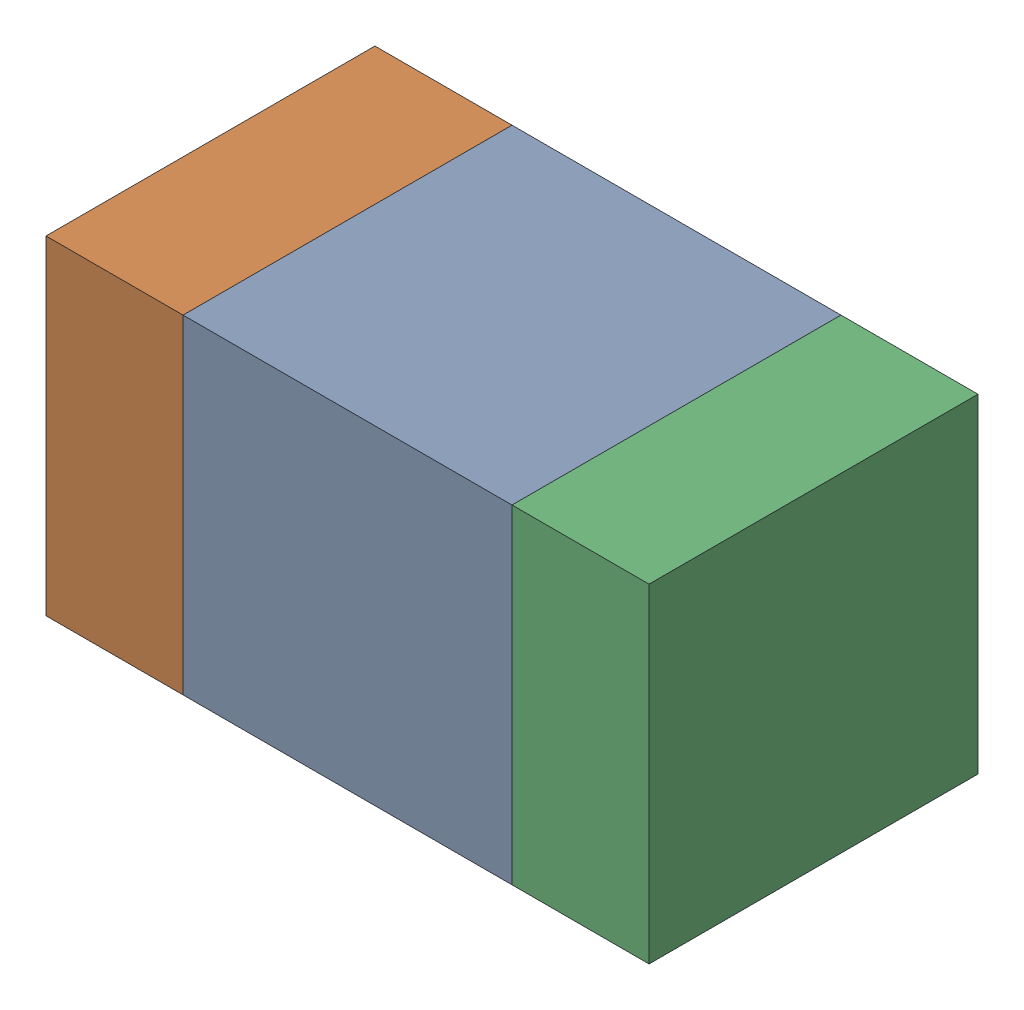
SolidWorks assembly C200PCB, configuration Default. Lengths in mm.
Overall size (1.1 0.6 0.6).
6 component instances, 2 part files, 0 mates.
Components (placement in the parent):
- 761606048-1: 761606048 [Default] at (121.6 124.5 -2.2638) size (0.6 0.6 0.6)
  - Extruded_9-1: Extruded_9 [Default] at origin size (0.6 0.6 0.6)
- 854785160-1: 854785160 [Default] at (121.175 124.5 -2.2638) size (0.25 0.6 0.6)
  - Extruded_19-1: Extruded_19 [Default] at origin size (0.25 0.6 0.6)
- 854785160-2: 854785160 [Default] at (122.025 124.5 -2.2638) size (0.25 0.6 0.6)
  - Extruded_19-1: Extruded_19 [Default] at origin size (0.25 0.6 0.6)
